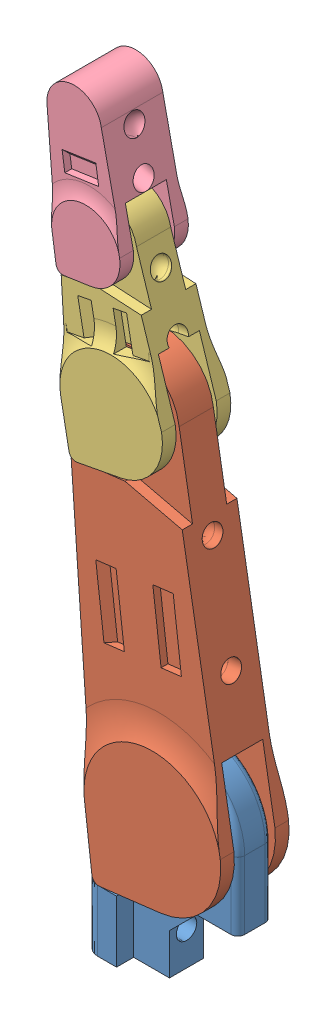
SolidWorks assembly rh1f2 v4, configuration Default. Lengths in mm.
4 component instances, 4 part files, 9 mates.
Components (placement in the parent):
- robot hand v4 f1 4-1: robot hand v4 f1 4 [Default] at (7.4493 16.7233 27.6774) x (0 1 0) z (0 0 1) size (30 20 10)
- rhf2l1-1: rhf2l1 [Default] at (4.4359 41.541 27.6774) x (-0.120535 0.992709 0) z (0 0 1) size (67.5 21.94 12)
- rhf1l2-1: rhf1l2 [Default] at (-0.4297 76.1857 27.6774) x (-0.18523 0.982695 0) z (0 0 1) size (32.5 16.23 12)
- rhf1l3-1: rhf1l3 [Default] at (-3.3782 93.4321 27.6774) x (-0.14615 0.989262 0) z (0 0 1) size (24 10.94 11)
Mates (geometry in assembly coordinates):
- Concentric1: concentric aligned: cylinder of robot hand v4 f1 4-1 through (7.4493 16.7233 30.1774) axis (0 0 -1) radius 3; cylinder of rhf2l1-1 through (7.4493 16.7233 32.6774) axis (0 0 -1) radius 2.5
- Concentric2: concentric aligned: cylinder of rhf2l1-1 through (1.4226 66.3587 32.1774) axis (0 0 -1) radius 3; cylinder of rhf1l2-1 through (1.4226 66.3587 32.6774) axis (0 0 -1) radius 2.5
- Concentric3: concentric aligned: cylinder of rhf1l2-1 through (-2.282 86.0126 32.1774) axis (0 0 -1) radius 3; cylinder of rhf1l3-1 through (-2.282 86.0126 32.6774) axis (0 0 -1) radius 2.5
- Width4: width: plane of robot hand v4 f1 4-1 through (7.4493 16.7233 30.1774) normal (0 0 1); plane of rhf2l1-1 through (7.4493 16.7233 25.1774) normal (0 0 -1); plane of robot hand v4 f1 4-1 through (4.4359 41.541 30.6774) normal (0 0 -1); plane of rhf2l1-1 through (4.4359 41.541 24.6774) normal (0 0 1)
- Width6: width: plane of rhf1l2-1 through (-0.4297 76.1857 30.1774) normal (0 0 1); plane of rhf1l3-1 through (-0.4297 76.1857 25.1774) normal (0 0 -1); plane of rhf1l2-1 through (-3.3782 93.4321 24.6774) normal (0 0 1); plane of rhf1l3-1 through (-3.3782 93.4321 30.6774) normal (0 0 -1)
- Coincident1: coincident aligned: plane of rhf1l2-1 through (-6.6681 75.8048 31.6774) normal (-0.998141 -0.06094 0); plane of rhf2l1-1 through (-4.2921 40.922 31.6774) normal (-0.997494 -0.070749 0)
- Coincident2: coincident aligned: plane of robot hand v4 f1 4-1 through (-2.5507 16.7233 30.1774) normal (-1 0 0); plane of rhf2l1-1 through (-4.2921 40.922 31.6774) normal (-0.997494 -0.070749 0)
- Coincident3: coincident aligned: plane of rhf1l2-1 through (-6.6681 75.8048 31.6774) normal (-0.998141 -0.06094 0); plane of rhf1l3-1 through (-7.8638 93.0727 29.6774) normal (-0.996805 -0.079874 0)
- Width7: width: plane of rhf2l1-1 through (4.4359 41.541 30.1774) normal (0 0 1); plane of rhf2l1-1 through (4.4359 41.541 25.1774) normal (0 0 -1); plane of rhf1l2-1 through (-0.4297 76.1857 30.6774) normal (0 0 -1); plane of rhf1l2-1 through (-0.4297 76.1857 24.6774) normal (0 0 1)
